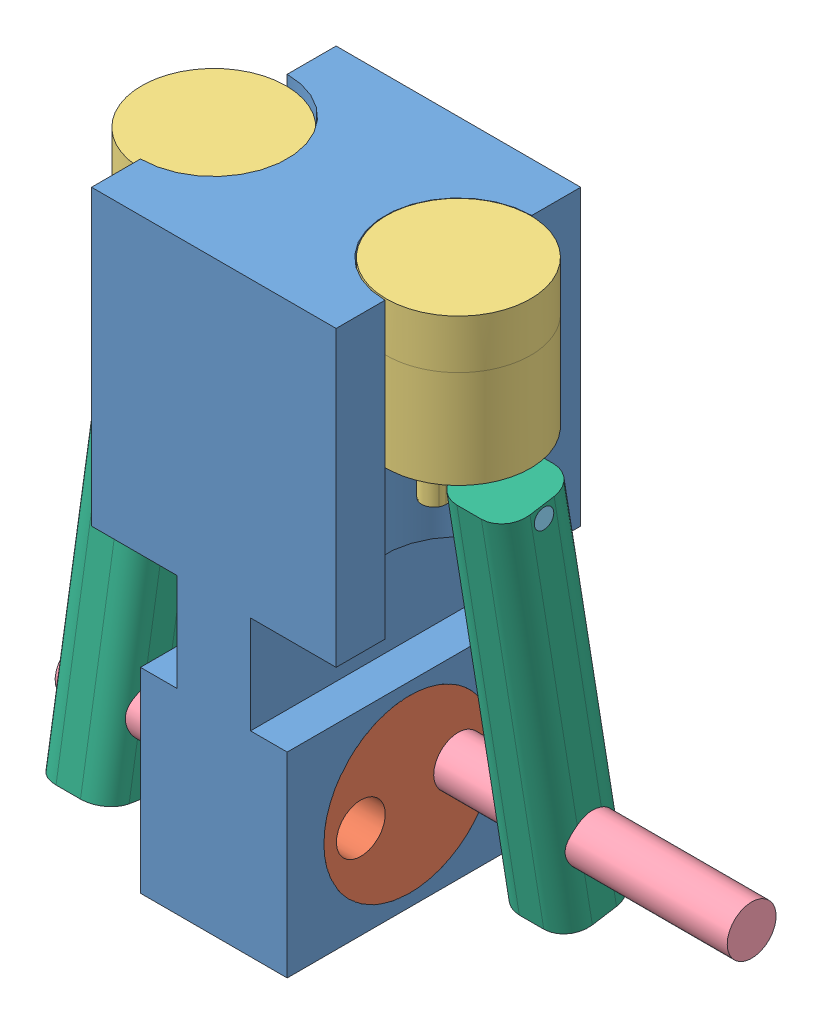
SolidWorks assembly Assem1, configuration Default. Lengths in mm.
Overall size (298.96 305.06 127).
11 component instances, 6 part files, 20 mates.
Components (placement in the parent):
- Part1-1: Part1 [Default] at origin size (127 304.8 127)
- Part2-1: Part2 [Default] at (101.6 -101.6 -63.5) x (0 0.1002 -0.994967) z (0 0.994967 0.1002) size (88.9 76.2 88.9)
- Part3-4: Part3 [Default] at (127 127.2633 -63.5) x (-1 0 0) z (0 0 1) size (74.93 101.6 74.93)
- Part3-6: Part3 [Default] at (0 122.1731 -63.5) x (1 0 0) z (0 0 -1) size (74.93 101.6 74.93)
- bigsil-1: bigsil [Default] at (139.7 -99.0549 -88.7722) x (0 0.797279 -0.60361) z (0 -0.60361 -0.797279) size (25.4 114.3 25.4)
- bigsil-2: bigsil [Default] at (25.4 -99.0549 -88.7722) x (0 0.99999 0.00454) z (0 0.00454 -0.99999) size (25.4 114.3 25.4)
- bigsil-3: bigsil [Default] at (-44.4417 -104.1451 -38.2278) x (0 0.694614 0.719383) z (0 0.719383 -0.694614) size (25.4 114.3 25.4)
- smallsil-1: smallsil [Default] at (5.844 52.3231 -63.5) x (0 0.410437 -0.911889) z (0 0.911889 0.410437) size (10.16 50.8 10.16)
- smallsil-2: smallsil [Default] at (120.6417 57.4133 -63.5) x (0 -1 0) z (0 0 1) size (10.16 50.8 10.16)
- Part4-9: Part4 [Default] at (152.3917 63.682 -62.4875) x (0 0.15945 -0.987206) z (-1 0 0) size (38.1 203.2 38.1)
- Part4-10: Part4 [Default] at (-25.3917 58.5919 -64.5125) x (0 -0.15945 -0.987206) z (-1 0 0) size (38.1 203.2 38.1)
Mates (geometry in assembly coordinates):
- Concentric1: concentric: cylinder of Part1-1 through (249.428 -101.6 -63.5) axis (-1 0 0) radius 44.45; cylinder of Part2-1 through (25.4 -101.6 -63.5) axis (1 0 0) radius 44.45
- Coincident1: coincident: plane of Part1-1 through (101.6 -50.8 13.716) normal (1 0 0); plane of Part2-1 through (101.6 -101.6 -63.5) normal (1 0 0)
- Concentric8: concentric: cylinder of Part1-1 through (127 152.4 -63.5) axis (0 -1 0) radius 38.1; cylinder of Part3-4 through (127 51.0633 -63.5) axis (0 1 0) radius 37.4396
- Concentric10: concentric: cylinder of Part1-1 through (0 0 -63.5) axis (0 1 0) radius 38.1; cylinder of Part3-6 through (0 45.9731 -63.5) axis (0 1 0) radius 37.4396
- Concentric11: concentric: cylinder of Part2-1 through (25.4 -99.0549 -88.7722) axis (1 0 0) radius 12.7; cylinder of bigsil-1 through (254 -99.0549 -88.7722) axis (-1 0 0) radius 12.7
- Coincident3: coincident: plane of bigsil-1 through (139.7 -99.0549 -88.7722) normal (-1 0 0); plane of bigsil-2 through (139.7 -99.0549 -88.7722) normal (1 0 0)
- Concentric16: concentric: cylinder of Part2-1 through (25.4 -104.1451 -38.2278) axis (1 0 0) radius 12.7; cylinder of bigsil-3 through (69.8583 -104.1451 -38.2278) axis (-1 0 0) radius 12.7
- Concentric20: concentric: cylinder of Part3-4 through (50.8 57.4133 -63.5) axis (1 0 0) radius 5.08; cylinder of smallsil-2 through (178.7573 57.4133 -63.5) axis (-1 0 0) radius 5.08
- Concentric24: concentric: cylinder of Part2-1 through (25.4 -99.0549 -88.7722) axis (1 0 0) radius 12.7; cylinder of bigsil-2 through (139.7 -99.0549 -88.7722) axis (-1 0 0) radius 12.7
- Concentric25: concentric: cylinder of bigsil-1 through (254 -99.0549 -88.7722) axis (-1 0 0) radius 12.7; cylinder of bigsil-2 through (139.7 -99.0549 -88.7722) axis (-1 0 0) radius 12.7
- Concentric27: concentric: cylinder of bigsil-2 through (139.7 -99.0549 -88.7722) axis (-1 0 0) radius 12.7; cylinder of Part4-9 through (76.1917 -99.0549 -88.7722) axis (1 0 0) radius 12.7
- Coincident5: coincident: plane of Part3-4 through (133.3417 76.4633 -50.7818) normal (1 0 0); plane of Part4-9 through (133.3417 -137.9307 -88.619) normal (-1 0 0)
- Concentric28: concentric: cylinder of smallsil-2 through (178.7573 57.4133 -63.5) axis (-1 0 0) radius 5.08; cylinder of Part4-9 through (76.1917 57.4133 -63.5) axis (1 0 0) radius 5.08
- Coincident6: coincident: plane of Part2-1 through (25.4 -101.6 -63.5) normal (-1 0 0); plane of bigsil-2 through (25.4 -99.0549 -88.7722) normal (-1 0 0)
- Concentric29: concentric: cylinder of Part3-6 through (76.2 52.3231 -63.5) axis (-1 0 0) radius 5.08; cylinder of smallsil-1 through (-44.956 52.3231 -63.5) axis (1 0 0) radius 5.08
- Concentric30: concentric: cylinder of bigsil-3 through (69.8583 -104.1451 -38.2278) axis (-1 0 0) radius 12.7; cylinder of Part4-10 through (-101.5917 -104.1451 -38.2278) axis (1 0 0) radius 12.7
- Coincident7: coincident: plane of Part3-6 through (-6.3417 71.3731 -76.2182) normal (-1 0 0); plane of Part4-10 through (-6.3417 -140.9959 -25.8435) normal (1 0 0)
- Concentric31: concentric: cylinder of smallsil-1 through (-44.956 52.3231 -63.5) axis (1 0 0) radius 5.08; cylinder of Part4-10 through (-101.5917 52.3231 -63.5) axis (1 0 0) radius 5.08
- Coincident8: coincident: plane of bigsil-3 through (-44.4417 -104.1451 -38.2278) normal (-1 0 0); circle of Part4-10
- Coincident9: coincident: plane of smallsil-2 through (171.4417 57.4133 -63.5) normal (1 0 0); plane of Part4-9 through (171.4417 -137.9307 -88.619) normal (1 0 0)
